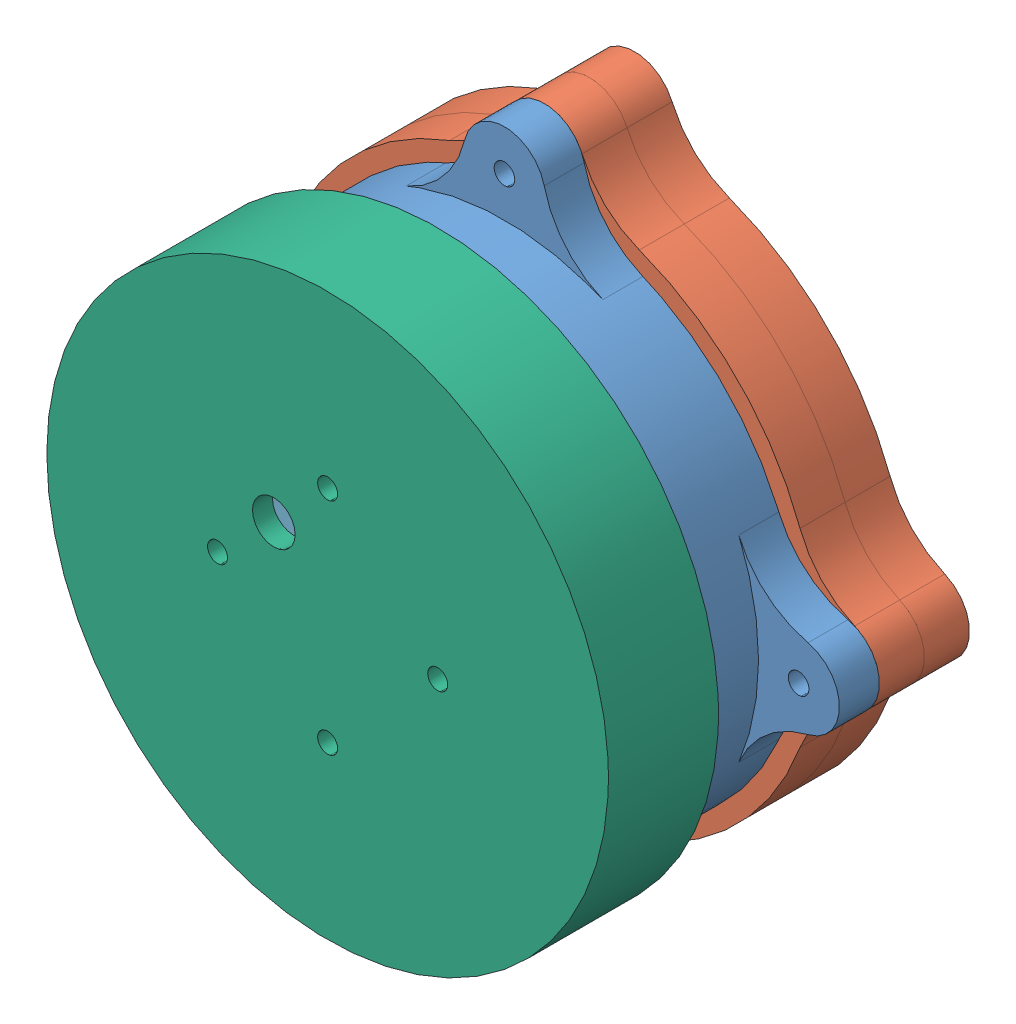
SolidWorks assembly harmonic, configuration Default. Lengths in mm.
Overall size (100.42 100.42 46).
6 component instances, 6 part files, 6 mates.
Components (placement in the parent):
- circular spline 2-1: circular spline 2 [Default] at (11.2097 57.3172 75.6018) size (100.42 100.42 24)
- Slew bearing^Assem1-1: Slew bearing^Assem1 [Default] at origin size (100.42 100.42 13.5)
- Slew bearing inner-1: Slew bearing inner [Default] at origin size (82.24 78.51 12.5)
- toroid-1: toroid [Default] at origin size (95.83 92.1 6.4)
- flex gear 3-1: flex gear 3 [Default] at (11.2097 57.3172 77.6018) x (-0.49576 -0.868459 0) z (0 0 1) size (57.6 57.6 36)
- motor holder^harmonic-1: motor holder^harmonic [Default] at (11.2097 57.3172 99.6018) size (84.17 84.17 16.5)
Mates (geometry in assembly coordinates):
- Coincident13: coincident anti-aligned: plane of Slew bearing inner-1 through (11.2097 57.3172 63.6018) normal (0 0 1); plane of flex gear 3-1 through (11.2097 57.3172 63.6018) normal (0 0 -1)
- Concentric1: concentric anti-aligned: circle of Slew bearing inner-1; circle of flex gear 3-1
- InPlace1: in place: plane of circular spline 2-1 through (11.2097 57.3172 99.6018) normal (0 0 1); plane of ? through (0 0 99.6018) normal (0 0 1); moOrthogonalPlaneRef_w of circular spline 2-1 through (11.2097 57.3172 99.6018) normal (0 0 1); plane of ? through (0 0 99.6018) normal (0 1 0); plane of circular spline 2-1 through (11.2097 57.3172 99.6018) normal (0 0 1); plane of ? through (0 0 99.6018) normal (1 0 0); plane of circular spline 2-1 through (11.2097 57.3172 99.6018) normal (0 0 1); unknown of motor holder^harmonic-1
- Coincident16: coincident aligned: plane of circular spline 2-1 through (11.2097 57.3172 99.6018) normal (0 0 1); plane of motor holder^harmonic-1 through (11.2097 57.3172 99.6018) normal (0 0 1)
- Coincident17: coincident aligned: moOrthogonalPlaneRef_w of circular spline 2-1 through (11.2097 57.3172 99.6018) normal (0 1 0); plane of motor holder^harmonic-1 through (11.2097 57.3172 99.6018) normal (0 1 0)
- Coincident18: coincident anti-aligned: moOrthogonalPlaneRef_w of circular spline 2-1 through (11.2097 57.3172 99.6018) normal (-1 0 0); plane of motor holder^harmonic-1 through (11.2097 57.3172 99.6018) normal (1 0 0)
